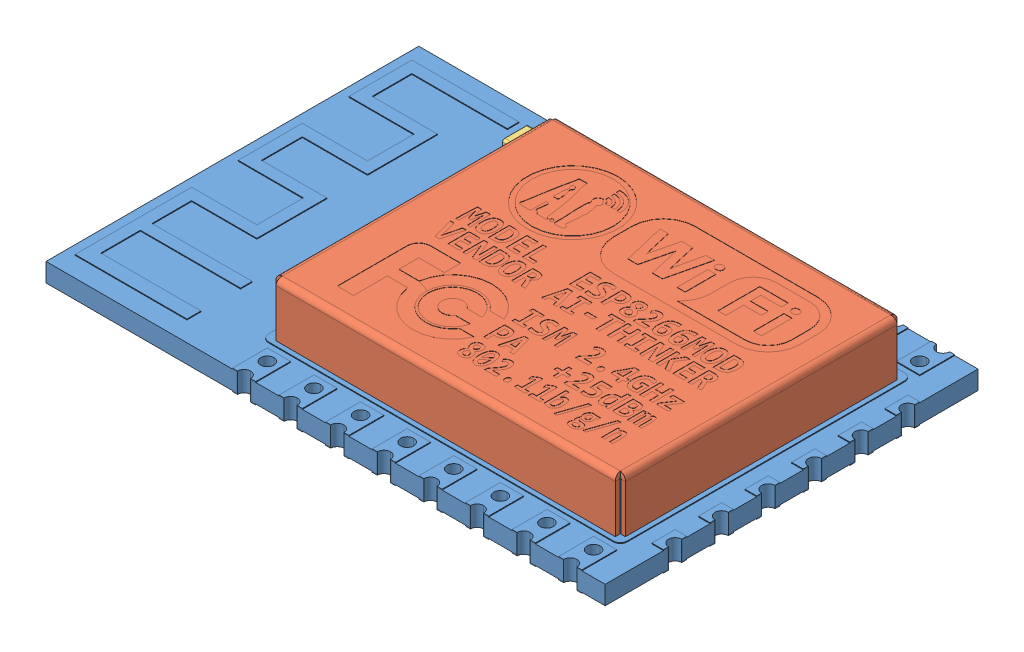
SolidWorks assembly ESP-12F, configuration Default. Lengths in mm.
Overall size (24 3.17 16).
4 component instances, 3 part files, 0 mates.
Components (placement in the parent):
- ESP-12F.STEP-1: ESP-12F.STEP [Default] at origin size (24 3.17 16)
  - Board.STEP-1: Board.STEP [Default] at origin size (24 0.87 16)
  - Shield.STEP-1: Shield.STEP [Default] at (3.2 3.17 0) x (1 0 0) z (0 0 -1) size (15.01 2.3 12.11)
  - LED-0603H0.75.STEP-1: LED-0603H0.75.STEP [Default] at (-5.5 0.87 -5.3) x (0 0 -1) z (0 1 0) size (1.7 0.9 0.75)
